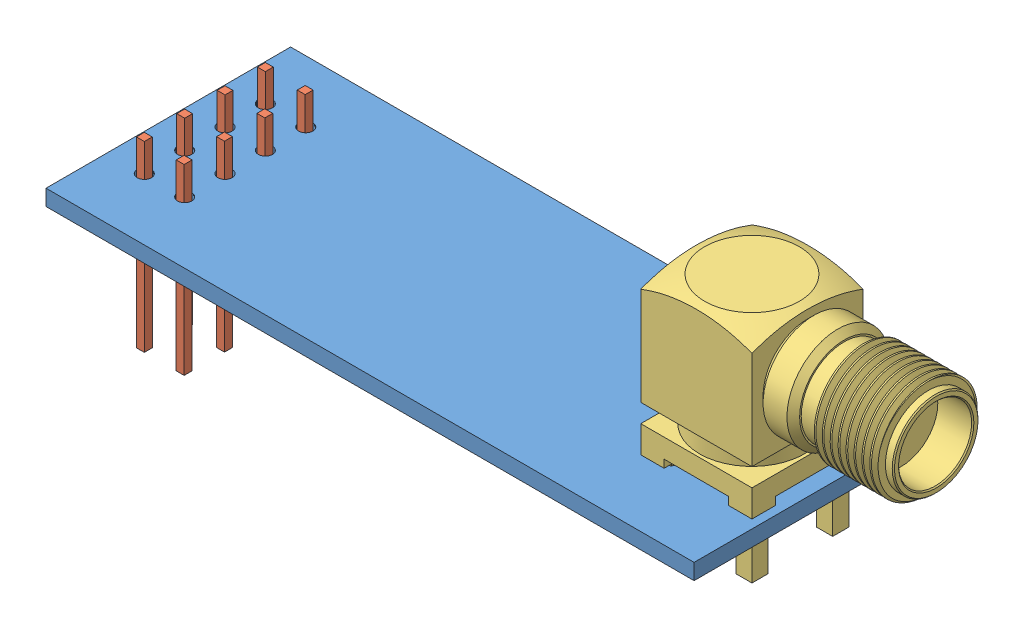
SolidWorks assembly User Library-NRF24+SMA, configuration По умолчанию. Lengths in mm.
Overall size (48.36 19.43 15.4).
3 component instances, 3 part files, 6 mates.
Components (placement in the parent):
- User Library-NRF24+SMA_plata-1: User Library-NRF24+SMA_plata [По умолчанию] at (-19.2488 1.4135 4.6356) size (40.8 1 15.4)
- User Library-NRF24+SMA_User Library-PLD-8-1: User Library-NRF24+SMA_User Library-PLD-8 [По умолчанию] at (-15.6788 1.4135 -0.5444) x (-1 0 0) z (0 0 1) size (5 11.5 10.16)
- User Library-NRF24+SMA_6RFX-1: User Library-NRF24+SMA_6RFX [Default] at (17.5112 2.4135 -3.0487) size (15.1 13.87 7.14)
Mates (geometry in assembly coordinates):
- Расстояние1: distance = 2.05 mm aligned: plane of User Library-NRF24+SMA_User Library-PLD-8-1 through (-17.1988 4.4135 -7.1244) normal (-1 0 0); plane of User Library-NRF24+SMA_plata-1 through (-19.2488 2.4135 4.6356) normal (-1 0 0)
- Расстояние2: distance = 3.64 mm aligned: plane of User Library-NRF24+SMA_User Library-PLD-8-1 through (-16.6988 4.4135 -7.1244) normal (0 0 -1); plane of User Library-NRF24+SMA_plata-1 through (-19.2488 2.4135 -10.7644) normal (0 0 -1)
- Совпадение2: coincident anti-aligned: plane of User Library-NRF24+SMA_plata-1 through (-19.2488 1.4135 4.6356) normal (0 -1 0); plane of User Library-NRF24+SMA_User Library-PLD-8-1 through (-17.1788 1.4135 1.9956) normal (0 1 0)
- Концентричный4: concentric anti-aligned: cylinder of User Library-NRF24+SMA_plata-1 through (17.5112 2.4135 -3.0487) axis (0 -1 0) radius 0.75; cylinder of User Library-NRF24+SMA_6RFX-1 through (17.5112 -3.3225 -3.0487) axis (0 1 0) radius 0.635
- Параллельность2: parallel aligned: plane of User Library-NRF24+SMA_plata-1 through (21.5512 2.4135 4.6356) normal (1 0 0); plane of User Library-NRF24+SMA_6RFX-1 through (21.0112 12.2735 0.4513) normal (1 0 0)
- Совпадение3: coincident anti-aligned: plane of User Library-NRF24+SMA_plata-1 through (-19.2488 2.4135 4.6356) normal (0 1 0); plane of User Library-NRF24+SMA_6RFX-1 through (17.5112 2.4135 -3.0487) normal (0 -1 0)
